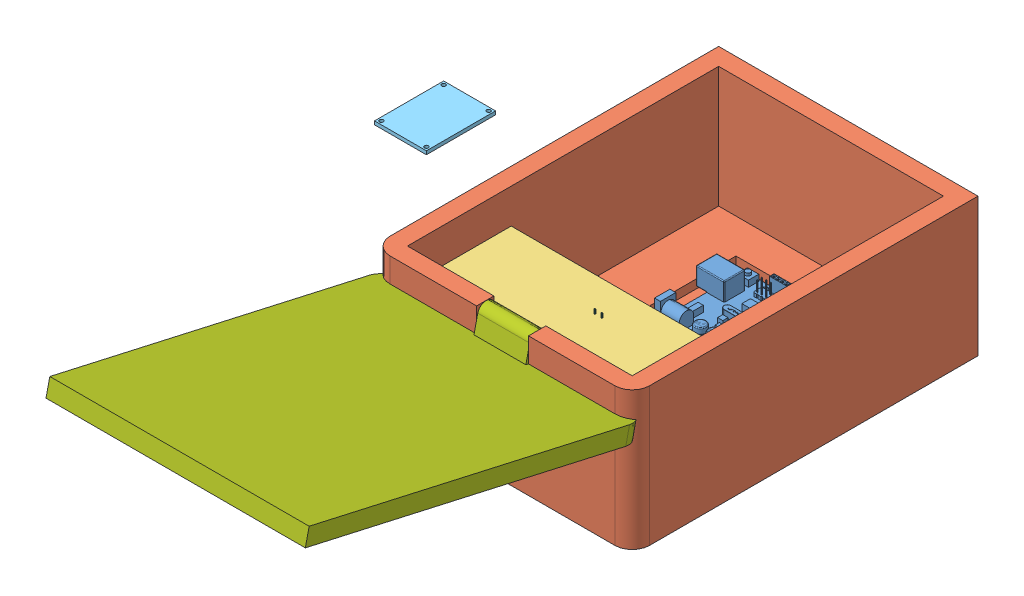
SolidWorks assembly alarm kebocoran airrrr, configuration Default. Lengths in mm.
Overall size (242.31 122.71 389.07).
8 component instances, 7 part files, 12 mates.
Components (placement in the parent):
- Arduino UNO-1: Arduino UNO [Predeterminado] at (1.2889 36.842 72.9584) size (74.8 15.1 53.3)
- case 1-1: case 1 [Default] at (17.9834 31.842 190.7083) size (150 80 200)
- tempat peletak buzzer-1: tempat peletak buzzer [Default] at (-75.7017 102.6754 167.254) x (0 0 1) z (0 1 0) size (50 135 5)
- paku-1: paku [Default] at (-30.7017 104.342 208.9631) x (0 0 1) z (0 1 0) size (5 15 5)
- paku-2: paku [Default] at (4.2983 104.342 208.9631) x (0 0 1) z (0 1 0) size (5 15 5)
- sensor pendeteksi hujan-2: sensor pendeteksi hujan [Default] at (-153.7919 81.7578 101.9188) x (0 0 -1) z (-1 0 0) size (44 6.5 30)
- buzzer-1: buzzer [Default] at (-0.7017 89.342 168.9631) x (1 0 0) z (0 0 -1) size (30 20 30)
- tutuppp nyaa-1: tutuppp nyaa [Default] at (149.6554 216.4117 785.4716) x (0 0.219987 0.975503) z (-1 0 0) size (200 25 150)
Mates (geometry in assembly coordinates):
- Coincident1: coincident: point of Arduino UNO-1; line of case 1-1 through (-40.7017 36.842 98.9631) axis (1 0 0)
- Coincident2: coincident aligned: line of Arduino UNO-1 through (34.2983 36.842 93.3631) axis (0 0 -1); line of case 1-1 through (34.2983 36.842 98.9631) axis (0 0 -1)
- Coincident3: coincident anti-aligned: plane of case 1-1 through (-75.7017 31.842 190.7083) normal (1 0 0); plane of tempat peletak buzzer-1 through (-75.7017 102.6754 167.254) normal (-1 0 0)
- Coincident4: coincident: point of case 1-1; point of tempat peletak buzzer-1
- Coincident5: coincident: point of case 1-1; point of tempat peletak buzzer-1
- Coincident6: coincident anti-aligned: plane of case 1-1 through (-30.7017 104.342 208.9631) normal (1 0 0); plane of paku-1 through (-30.7017 104.342 208.9631) normal (-1 0 0)
- Concentric1: concentric anti-aligned: cylinder of case 1-1 through (-30.7017 104.342 208.9631) axis (1 0 0) radius 2.5; cylinder of paku-1 through (-15.7017 104.342 208.9631) axis (-1 0 0) radius 2.5
- Coincident7: coincident anti-aligned: plane of case 1-1 through (19.2983 104.342 208.9631) normal (-1 0 0); plane of paku-2 through (19.2983 104.342 208.9631) normal (1 0 0)
- Concentric2: concentric anti-aligned: cylinder of case 1-1 through (-30.7017 104.342 208.9631) axis (1 0 0) radius 2.5; cylinder of paku-2 through (19.2983 104.342 208.9631) axis (-1 0 0) radius 2.5
- Coincident8: coincident aligned: circle of tempat peletak buzzer-1; circle of buzzer-1
- Coincident9: coincident anti-aligned: plane of paku-2 through (4.2983 104.342 208.9631) normal (-1 0 0); plane of tutuppp nyaa-1 through (4.2983 104.342 208.9631) normal (1 0 0)
- Concentric3: concentric anti-aligned: cylinder of paku-2 through (19.2983 104.342 208.9631) axis (-1 0 0) radius 2.5; cylinder of tutuppp nyaa-1 through (4.2983 104.342 208.9631) axis (1 0 0) radius 2.5
